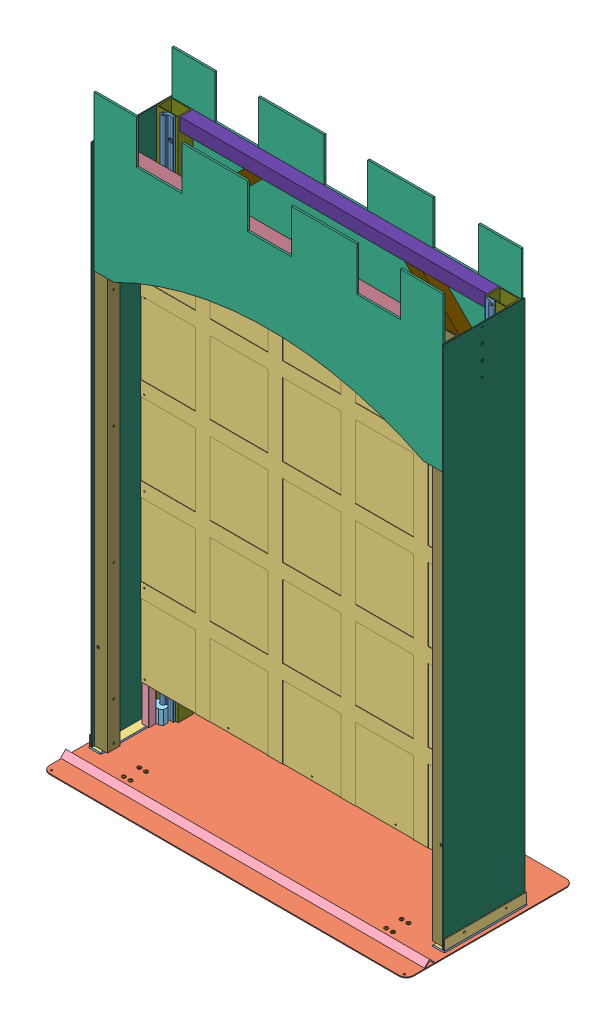
SolidWorks assembly GE-16157_ASM, configuration Default. Lengths in mm.
Overall size (1270 2060.58 584.2).
152 component instances, 24 part files, 0 mates.
Components (placement in the parent):
- GE-16158_ASM-1: GE-16158_ASM [Default] at origin size (1270 114.3 584.2)
  - GE-16159_ASM-1: GE-16159_ASM [Default] at origin size (1270 53.82 584.2)
    - GE-16159_ASM-1: GE-16159_ASM [Default] at origin size (1244.6 3.17 292.1)
    - GE-16016-1: GE-16016 [Default] at origin size (1270 3.17 584.2)
    - GE-16159-01-1: GE-16159-01 [Default] at (619.125 3.175 0) x (0 0 1) z (-1 0 0) size (285.75 38.1 38.1)
    - GE-16159-01-2: GE-16159-01 [Default] at (-619.125 3.175 0) x (0 0 -1) z (1 0 0) size (285.75 38.1 38.1)
    - GE-16159-02-1: GE-16159-02 [Default] at (0 23.3806 210.6395) x (1 0 0) z (0 0.707107 -0.707107) size (1270 25.4 25.4)
  - GE-16150-1: GE-16150 [Default] at (469.9 -3.175 173.0375) size (15.88 6.35 15.88)
  - GE-16150-2: GE-16150 [Default] at (469.9 -3.175 119.0625) size (15.88 6.35 15.88)
  - GE-16150-3: GE-16150 [Default] at (446.0875 -3.175 173.0375) size (15.88 6.35 15.88)
  - GE-16150-4: GE-16150 [Default] at (446.0875 -3.175 119.0625) size (15.88 6.35 15.88)
  - GE-16150-5: GE-16150 [Default] at (292.1127 -3.175 -207.9625) size (15.88 6.35 15.88)
  - GE-16150-6: GE-16150 [Default] at (292.1127 -3.175 -261.9375) size (15.88 6.35 15.88)
  - GE-16150-7: GE-16150 [Default] at (268.3002 -3.175 -207.9625) size (15.88 6.35 15.88)
  - GE-16150-8: GE-16150 [Default] at (268.3002 -3.175 -261.9375) size (15.88 6.35 15.88)
  - GE-16150-9: GE-16150 [Default] at (-268.3002 -3.175 -207.9625) size (15.88 6.35 15.88)
  - GE-16150-10: GE-16150 [Default] at (-268.3002 -3.175 -261.9375) size (15.88 6.35 15.88)
  - GE-16150-11: GE-16150 [Default] at (-292.1127 -3.175 -261.9375) size (15.88 6.35 15.88)
  - GE-16150-12: GE-16150 [Default] at (-292.1127 -3.175 -207.9625) size (15.88 6.35 15.88)
  - GE-16150-13: GE-16150 [Default] at (-446.0875 -3.175 119.0625) size (15.88 6.35 15.88)
  - GE-16150-14: GE-16150 [Default] at (-446.0875 -3.175 173.0375) size (15.88 6.35 15.88)
  - GE-16150-15: GE-16150 [Default] at (-469.9 -3.175 119.0625) size (15.88 6.35 15.88)
  - GE-16150-16: GE-16150 [Default] at (-469.9 -3.175 173.0375) size (15.88 6.35 15.88)
  - GE-16017-1: GE-16017 [Default] at (457.9937 -9.525 146.05) x (0 0 -1) z (1 0 0) size (101.6 3.17 101.6)
  - GE-16017-2: GE-16017 [Default] at (280.2065 -9.525 -234.95) x (0 0 -1) z (1 0 0) size (101.6 3.17 101.6)
  - GE-16017-3: GE-16017 [Default] at (-280.2065 -9.525 -234.95) x (0 0 -1) z (1 0 0) size (101.6 3.17 101.6)
  - GE-16017-4: GE-16017 [Default] at (-457.9937 -9.525 146.05) x (0 0 -1) z (1 0 0) size (101.6 3.17 101.6)
  - GE-16151_ASM-1: GE-16151_ASM [Default] at (457.9937 -47.625 163.5125) size (47.62 63.5 75.41)
    - GE-16151-01_ASM-1: GE-16151-01_ASM [Default] at origin size (47.62 63.5 75.41)
      - GE-16151-02-1: GE-16151-02 [Default] at origin size (27.94 50.8 50.8)
      - GE-16151-03-1: GE-16151-03 [Default] at origin size (47.62 47.55 65.09)
  - GE-16151_ASM-2: GE-16151_ASM [Default] at (280.2065 -47.625 -217.4875) size (47.62 63.5 75.41)
    - GE-16151-01_ASM-1: GE-16151-01_ASM [Default] at origin size (47.62 63.5 75.41)
      - GE-16151-02-1: GE-16151-02 [Default] at origin size (27.94 50.8 50.8)
      - GE-16151-03-1: GE-16151-03 [Default] at origin size (47.62 47.55 65.09)
  - GE-16151_ASM-3: GE-16151_ASM [Default] at (-280.2065 -47.625 -217.4875) size (47.62 63.5 75.41)
    - GE-16151-01_ASM-1: GE-16151-01_ASM [Default] at origin size (47.62 63.5 75.41)
      - GE-16151-02-1: GE-16151-02 [Default] at origin size (27.94 50.8 50.8)
      - GE-16151-03-1: GE-16151-03 [Default] at origin size (47.62 47.55 65.09)
  - GE-16151_ASM-4: GE-16151_ASM [Default] at (-457.9937 -47.625 163.5125) size (47.62 63.5 75.41)
    - GE-16151-01_ASM-1: GE-16151-01_ASM [Default] at origin size (47.62 63.5 75.41)
      - GE-16151-02-1: GE-16151-02 [Default] at origin size (27.94 50.8 50.8)
      - GE-16151-03-1: GE-16151-03 [Default] at origin size (47.62 47.55 65.09)
  - HW-00086-1: HW-00086 [Default] at (-292.1127 -22.225 -261.9375) x (-1 0 0) z (0 1 0) size (12.59 12.5 29.99)
  - HW-00086-2: HW-00086 [Default] at (-268.3002 -22.225 -261.9375) x (-1 0 0) z (0 1 0) size (12.59 12.5 29.99)
  - HW-00086-3: HW-00086 [Default] at (-292.1127 -22.225 -207.9625) x (-1 0 0) z (0 1 0) size (12.59 12.5 29.99)
  - HW-00086-4: HW-00086 [Default] at (-268.3002 -22.225 -207.9625) x (-1 0 0) z (0 1 0) size (12.59 12.5 29.99)
  - HW-00086-5: HW-00086 [Default] at (-469.9 -22.225 173.0375) x (-1 0 0) z (0 1 0) size (12.59 12.5 29.99)
  - HW-00086-6: HW-00086 [Default] at (-446.0875 -22.225 173.0375) x (-1 0 0) z (0 1 0) size (12.59 12.5 29.99)
  - HW-00086-7: HW-00086 [Default] at (-446.0875 -22.225 119.0625) x (-1 0 0) z (0 1 0) size (12.59 12.5 29.99)
  - HW-00086-8: HW-00086 [Default] at (-469.9 -22.225 119.0625) x (-1 0 0) z (0 1 0) size (12.59 12.5 29.99)
  - HW-00086-9: HW-00086 [Default] at (268.3002 -22.225 -261.9375) x (-1 0 0) z (0 1 0) size (12.59 12.5 29.99)
  - HW-00086-10: HW-00086 [Default] at (292.1127 -22.225 -261.9375) x (-1 0 0) z (0 1 0) size (12.59 12.5 29.99)
  - HW-00086-11: HW-00086 [Default] at (292.1127 -22.225 -207.9625) x (-1 0 0) z (0 1 0) size (12.59 12.5 29.99)
  - HW-00086-12: HW-00086 [Default] at (268.3002 -22.225 -207.9625) x (-1 0 0) z (0 1 0) size (12.59 12.5 29.99)
  - HW-00086-13: HW-00086 [Default] at (469.9 -22.225 119.0625) x (-1 0 0) z (0 1 0) size (12.59 12.5 29.99)
  - HW-00086-14: HW-00086 [Default] at (446.0875 -22.225 119.0625) x (-1 0 0) z (0 1 0) size (12.59 12.5 29.99)
  - HW-00086-15: HW-00086 [Default] at (469.9 -22.225 173.0375) x (-1 0 0) z (0 1 0) size (12.59 12.5 29.99)
  - HW-00086-16: HW-00086 [Default] at (446.0875 -22.225 173.0375) x (-1 0 0) z (0 1 0) size (12.59 12.5 29.99)
  - HW-00087_ASM-1: HW-00087_ASM [Default] at (469.9 -11.1125 173.0375) x (-1 0 0) z (0 0 1) size (11.11 8.13 12.83)
    - HW-00087-01_ASM-1: HW-00087-01_ASM [Default] at origin size (11.11 8.13 12.83)
      - HW-00087-02-1: HW-00087-02 [Default] at origin size (10.65 1.02 10.65)
      - HW-00087-03-1: HW-00087-03 [Default] at origin size (11.11 8.13 12.83)
  - HW-00087_ASM-2: HW-00087_ASM [Default] at (469.9 -11.1125 119.0625) x (-1 0 0) z (0 0 1) size (11.11 8.13 12.83)
    - HW-00087-01_ASM-1: HW-00087-01_ASM [Default] at origin size (11.11 8.13 12.83)
      - HW-00087-02-1: HW-00087-02 [Default] at origin size (10.65 1.02 10.65)
      - HW-00087-03-1: HW-00087-03 [Default] at origin size (11.11 8.13 12.83)
  - HW-00087_ASM-3: HW-00087_ASM [Default] at (446.0875 -11.1125 173.0375) x (-1 0 0) z (0 0 1) size (11.11 8.13 12.83)
    - HW-00087-01_ASM-1: HW-00087-01_ASM [Default] at origin size (11.11 8.13 12.83)
      - HW-00087-02-1: HW-00087-02 [Default] at origin size (10.65 1.02 10.65)
      - HW-00087-03-1: HW-00087-03 [Default] at origin size (11.11 8.13 12.83)
  - HW-00087_ASM-4: HW-00087_ASM [Default] at (446.0875 -11.1125 119.0625) x (-1 0 0) z (0 0 1) size (11.11 8.13 12.83)
    - HW-00087-01_ASM-1: HW-00087-01_ASM [Default] at origin size (11.11 8.13 12.83)
      - HW-00087-02-1: HW-00087-02 [Default] at origin size (10.65 1.02 10.65)
      - HW-00087-03-1: HW-00087-03 [Default] at origin size (11.11 8.13 12.83)
  - HW-00087_ASM-5: HW-00087_ASM [Default] at (268.3002 -11.1125 -207.9625) x (-1 0 0) z (0 0 1) size (11.11 8.13 12.83)
    - HW-00087-01_ASM-1: HW-00087-01_ASM [Default] at origin size (11.11 8.13 12.83)
      - HW-00087-02-1: HW-00087-02 [Default] at origin size (10.65 1.02 10.65)
      - HW-00087-03-1: HW-00087-03 [Default] at origin size (11.11 8.13 12.83)
  - HW-00087_ASM-6: HW-00087_ASM [Default] at (292.1127 -11.1125 -207.9625) x (-1 0 0) z (0 0 1) size (11.11 8.13 12.83)
    - HW-00087-01_ASM-1: HW-00087-01_ASM [Default] at origin size (11.11 8.13 12.83)
      - HW-00087-02-1: HW-00087-02 [Default] at origin size (10.65 1.02 10.65)
      - HW-00087-03-1: HW-00087-03 [Default] at origin size (11.11 8.13 12.83)
  - HW-00087_ASM-7: HW-00087_ASM [Default] at (268.3002 -11.1125 -261.9375) x (-1 0 0) z (0 0 1) size (11.11 8.13 12.83)
    - HW-00087-01_ASM-1: HW-00087-01_ASM [Default] at origin size (11.11 8.13 12.83)
      - HW-00087-02-1: HW-00087-02 [Default] at origin size (10.65 1.02 10.65)
      - HW-00087-03-1: HW-00087-03 [Default] at origin size (11.11 8.13 12.83)
  - HW-00087_ASM-8: HW-00087_ASM [Default] at (292.1127 -11.1125 -261.9375) x (-1 0 0) z (0 0 1) size (11.11 8.13 12.83)
    - HW-00087-01_ASM-1: HW-00087-01_ASM [Default] at origin size (11.11 8.13 12.83)
      - HW-00087-02-1: HW-00087-02 [Default] at origin size (10.65 1.02 10.65)
      - HW-00087-03-1: HW-00087-03 [Default] at origin size (11.11 8.13 12.83)
  - HW-00087_ASM-9: HW-00087_ASM [Default] at (-292.1127 -11.1125 -207.9625) x (-1 0 0) z (0 0 1) size (11.11 8.13 12.83)
    - HW-00087-01_ASM-1: HW-00087-01_ASM [Default] at origin size (11.11 8.13 12.83)
      - HW-00087-02-1: HW-00087-02 [Default] at origin size (10.65 1.02 10.65)
      - HW-00087-03-1: HW-00087-03 [Default] at origin size (11.11 8.13 12.83)
  - HW-00087_ASM-10: HW-00087_ASM [Default] at (-268.3002 -11.1125 -207.9625) x (-1 0 0) z (0 0 1) size (11.11 8.13 12.83)
    - HW-00087-01_ASM-1: HW-00087-01_ASM [Default] at origin size (11.11 8.13 12.83)
      - HW-00087-02-1: HW-00087-02 [Default] at origin size (10.65 1.02 10.65)
      - HW-00087-03-1: HW-00087-03 [Default] at origin size (11.11 8.13 12.83)
  - HW-00087_ASM-11: HW-00087_ASM [Default] at (-292.1127 -11.1125 -261.9375) x (-1 0 0) z (0 0 1) size (11.11 8.13 12.83)
    - HW-00087-01_ASM-1: HW-00087-01_ASM [Default] at origin size (11.11 8.13 12.83)
      - HW-00087-02-1: HW-00087-02 [Default] at origin size (10.65 1.02 10.65)
      - HW-00087-03-1: HW-00087-03 [Default] at origin size (11.11 8.13 12.83)
  - HW-00087_ASM-12: HW-00087_ASM [Default] at (-268.3002 -11.1125 -261.9375) x (-1 0 0) z (0 0 1) size (11.11 8.13 12.83)
    - HW-00087-01_ASM-1: HW-00087-01_ASM [Default] at origin size (11.11 8.13 12.83)
      - HW-00087-02-1: HW-00087-02 [Default] at origin size (10.65 1.02 10.65)
      - HW-00087-03-1: HW-00087-03 [Default] at origin size (11.11 8.13 12.83)
  - HW-00087_ASM-13: HW-00087_ASM [Default] at (-469.9 -11.1125 119.0625) x (-1 0 0) z (0 0 1) size (11.11 8.13 12.83)
    - HW-00087-01_ASM-1: HW-00087-01_ASM [Default] at origin size (11.11 8.13 12.83)
      - HW-00087-02-1: HW-00087-02 [Default] at origin size (10.65 1.02 10.65)
      - HW-00087-03-1: HW-00087-03 [Default] at origin size (11.11 8.13 12.83)
  - HW-00087_ASM-14: HW-00087_ASM [Default] at (-446.0875 -11.1125 119.0625) x (-1 0 0) z (0 0 1) size (11.11 8.13 12.83)
    - HW-00087-01_ASM-1: HW-00087-01_ASM [Default] at origin size (11.11 8.13 12.83)
      - HW-00087-02-1: HW-00087-02 [Default] at origin size (10.65 1.02 10.65)
      - HW-00087-03-1: HW-00087-03 [Default] at origin size (11.11 8.13 12.83)
  - HW-00087_ASM-15: HW-00087_ASM [Default] at (-469.9 -11.1125 173.0375) x (-1 0 0) z (0 0 1) size (11.11 8.13 12.83)
    - HW-00087-01_ASM-1: HW-00087-01_ASM [Default] at origin size (11.11 8.13 12.83)
      - HW-00087-02-1: HW-00087-02 [Default] at origin size (10.65 1.02 10.65)
      - HW-00087-03-1: HW-00087-03 [Default] at origin size (11.11 8.13 12.83)
  - HW-00087_ASM-16: HW-00087_ASM [Default] at (-446.0875 -11.1125 173.0375) x (-1 0 0) z (0 0 1) size (11.11 8.13 12.83)
    - HW-00087-01_ASM-1: HW-00087-01_ASM [Default] at origin size (11.11 8.13 12.83)
      - HW-00087-02-1: HW-00087-02 [Default] at origin size (10.65 1.02 10.65)
      - HW-00087-03-1: HW-00087-03 [Default] at origin size (11.11 8.13 12.83)
- GE-16160_ASM-1: GE-16160_ASM [Default] at (589.35 6.35 111.125) x (0 0 -1) z (1 0 0) size (285.75 1981.41 1229.61)
  - GE-16161_ASM-1: GE-16161_ASM [Default] at origin size (44.45 1828.8 1223.26)
    - GE-16161-01-1: GE-16161-01 [Default] at origin size (44.45 1828.8 44.45)
    - GE-16161-02-1: GE-16161-02 [Default] at (-22.225 1784.35 -1156.589) size (44.45 44.45 1134.36)
    - GE-16161-01-2: GE-16161-01 [Default] at (0 0 -1178.814) x (-1 0 0) z (0 0 -1) size (44.45 1828.8 44.45)
    - GE-16161-03-1: GE-16161-03 [Default] at (-22.225 1784.35 -246.7314) x (1 0 0) z (0 0.707107 -0.707107) size (44.45 44.45 406.4)
    - GE-16161-03-2: GE-16161-03 [Default] at (-22.225 1559.8436 -1156.589) x (1 0 0) z (0 -0.707107 -0.707107) size (44.45 44.45 406.4)
  - GE-16163-1: GE-16163 [Default] at (111.125 914.4 -1201.039) x (0 0 -1) z (0 -1 0) size (3.17 285.75 1828.8)
  - GE-16163-2: GE-16163 [Default] at (111.125 914.4 22.225) x (0 0 1) z (0 -1 0) size (3.17 285.75 1828.8)
  - GE-16162_ASM-1: GE-16162_ASM [Default] at (219.075 0 -15.875) size (50.8 1828.8 1223.26)
    - GE-16162-01-1: GE-16162-01 [Default] at origin size (50.8 1828.8 76.2)
    - GE-16162-02-1: GE-16162-02 [Default] at (-19.05 1784.35 -1108.964) size (44.45 44.45 1070.86)
    - GE-16162-01-2: GE-16162-01 [Default] at (0 0 -1147.064) x (-1 0 0) z (0 0 -1) size (50.8 1828.8 76.2)
    - GE-16162-03-1: GE-16162-03 [Default] at (-19.05 1559.8436 -38.1) x (1 0 0) z (0 0.707107 -0.707107) size (44.45 44.45 406.4)
    - GE-16162-03-2: GE-16162-03 [Default] at (-19.05 1784.35 -884.4576) x (1 0 0) z (0 -0.707107 -0.707107) size (44.45 44.45 406.4)
  - GE-16164-1: GE-16164 [Default] at (193.675 -0.2 -1134.364) x (0 0 1) z (-1 0 0) size (37 1829.02 22)
  - GE-16164-2: GE-16164 [Default] at (193.675 1828.8 -44.45) x (0 0 -1) z (-1 0 0) size (37 1829.02 22)
  - GE-16165_ASM-1: GE-16165_ASM [Default] at (139.975 1571.625 -17.85) x (-1 0 0) z (0 -1 0) size (68.08 1193.8 1584.33)
    - GE-16166-01-1: GE-16166-01 [Default] at origin size (25.4 1143 25.4)
    - GE-16167-1: GE-16167 [Default] at (15.875 571.5 715.9625) x (0 -1 0) z (-1 0 0) size (1193.8 1457.33 3.18)
    - GE-16166-02-1: GE-16166-02 [Default] at (0 1155.7 -12.7) x (1 0 0) z (0 -1 0) size (25.4 1584.33 25.4)
    - GE-16166-02-2: GE-16166-02 [Default] at (0 -12.7 -12.7) x (-1 0 0) z (0 1 0) size (25.4 1584.33 25.4)
    - GE-16166-01-2: GE-16166-01 [Default] at (0 1143 1431.925) x (1 0 0) z (0 0 -1) size (25.4 1143 25.4)
    - GE-16168-1: GE-16168 [Default] at (-39.7 -2.4 1523.625) x (0 1 0) z (1 0 0) size (44 48 39.5)
    - GE-16168-2: GE-16168 [Default] at (-39.7 -2.4 1063.625) x (0 1 0) z (1 0 0) size (44 48 39.5)
    - GE-16168-3: GE-16168 [Default] at (-39.7 1145.4 1571.625) x (0 -1 0) z (1 0 0) size (44 48 39.5)
    - GE-16168-4: GE-16168 [Default] at (-39.7 1145.4 1111.625) x (0 -1 0) z (1 0 0) size (44 48 39.5)
  - GE-16169-1: GE-16169 [Default] at (-28.575 1635.125 -587.375) x (0 0 -1) z (1 0 0) size (1219.2 539.75 6.35)
  - GE-16169-2: GE-16169 [Default] at (250.825 1635.125 -587.375) x (0 0 1) z (-1 0 0) size (1219.2 539.75 6.35)
